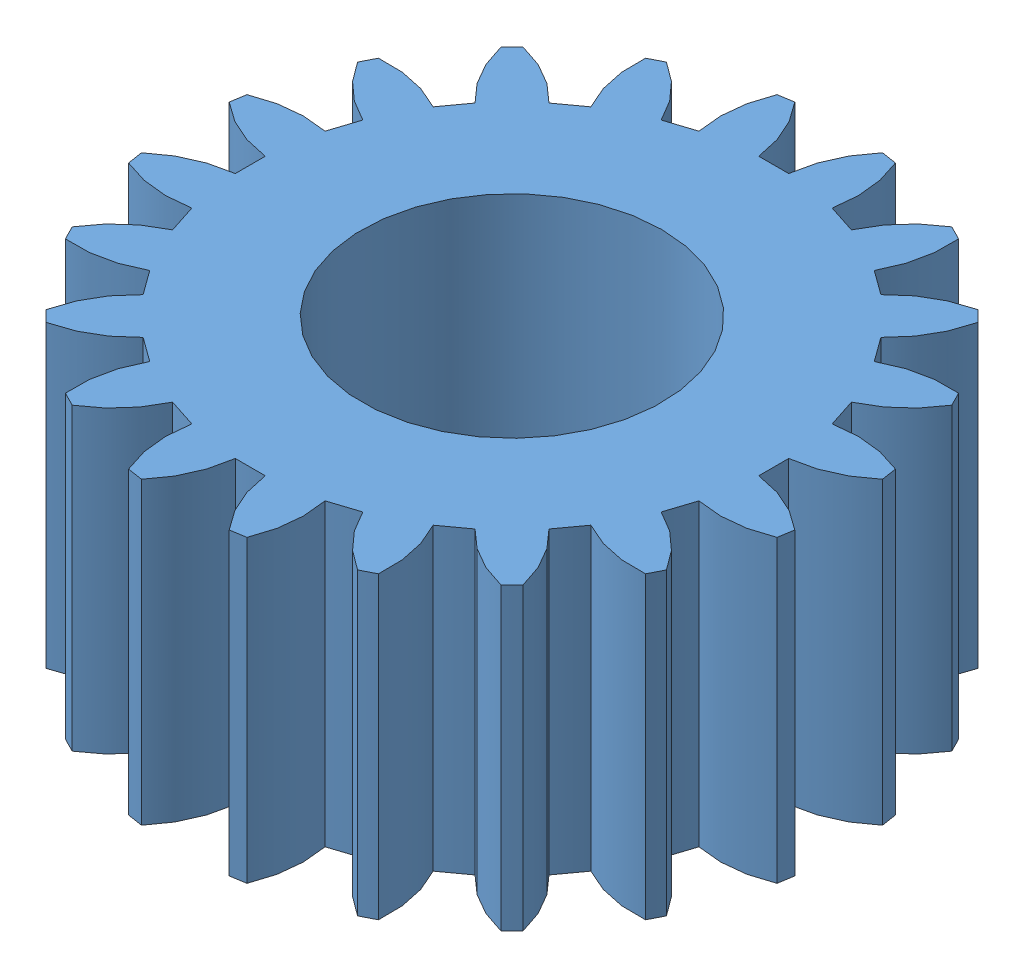
SolidWorks assembly Ensamblaje2, configuration Predeterminado. Lengths in mm.
Overall size (21.8 10 21.8).
2 component instances, 2 part files, 1 mates.
Components (placement in the parent):
- Planeta-1: Planeta [ISO - Spur gear 1M 20T 20PA 10FW ---S20A75H50L0.8N] x (0 1 0) z (0 0 1) size (10 21.8 21.8) (hidden)
- Copia de Pieza3-1: Copia de Pieza3 [Predeterminado] at origin size (21.8 10 21.8)
Mates (geometry in assembly coordinates):
- Coincidente1: coincident: plane of assembly through (0 0 0) normal (0 1 0); plane of Planeta-1 through (0 0 0) normal (0 -1 0); plane of assembly
